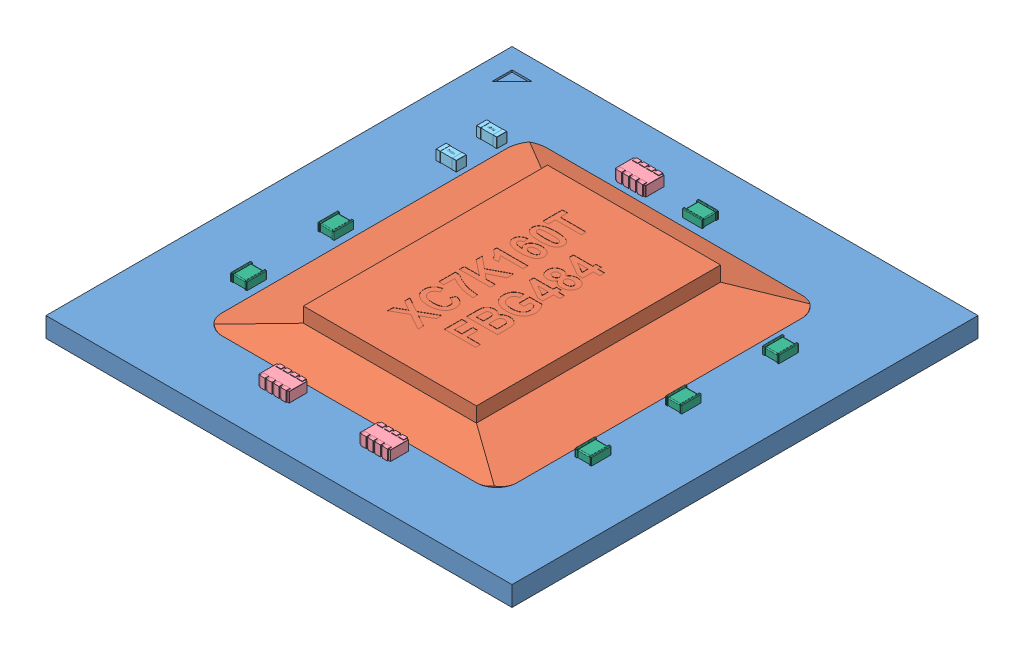
SolidWorks assembly FBG484, configuration Default. Lengths in mm.
Overall size (23 2.57 23).
25 component instances, 6 part files, 50 mates.
Components (placement in the parent):
- Substrate-1: Substrate [Default] at (0 0.3 0) size (23 0.98 23)
- Die-1: Die [Default] at (0 1.28 0) size (14.54 1.79 16.05)
- Ball-1: Ball [Default] at (10.5 0.15 -10.5) size (0.7 0.3 0.7)
- Ball-2: Ball [Default] at (10.5 0.15 -9.5) x (-1 0 0) z (0 0 1) size (0.7 0.3 0.7)
- Ball-3: Ball [Default] at (9.5 0.15 -10.5) x (0 0 -1) z (-1 0 0) size (0.7 0.3 0.7)
- Ball-4: Ball [Default] at (10.5 0.15 10.5) size (0.7 0.3 0.7)
- Ball-5: Ball [Default] at (10.5 0.15 9.5) x (-1 0 0) z (0 0 1) size (0.7 0.3 0.7)
- Ball-6: Ball [Default] at (9.5 0.15 10.5) x (0 0 1) z (1 0 0) size (0.7 0.3 0.7)
- Ball-7: Ball [Default] at (-10.5 0.15 -10.5) x (-1 0 0) z (0 0 -1) size (0.7 0.3 0.7)
- Ball-8: Ball [Default] at (-10.5 0.15 -9.5) x (1 0 0) z (0 0 -1) size (0.7 0.3 0.7)
- Ball-9: Ball [Default] at (-9.5 0.15 -10.5) x (0 0 -1) z (-1 0 0) size (0.7 0.3 0.7)
- Ball-10: Ball [Default] at (-10.5 0.15 10.5) x (-1 0 0) z (0 0 -1) size (0.7 0.3 0.7)
- Ball-11: Ball [Default] at (-10.5 0.15 9.5) x (1 0 0) z (0 0 -1) size (0.7 0.3 0.7)
- Ball-12: Ball [Default] at (-9.5 0.15 10.5) x (0 0 1) z (1 0 0) size (0.7 0.3 0.7)
- CARRAY-1: CARRAY [Default] at (-2.5 1.28 -8.8) size (1.5 0.52 1)
- CARRAY-2: CARRAY [Default] at (-2.5 1.28 8.8) size (1.5 0.52 1)
- CARRAY-3: CARRAY [Default] at (2.5 1.28 8.8) size (1.5 0.52 1)
- C0402-1: C0402 [0402] at (-8 1.28 -7) size (1 0.5 0.5)
- C0402-2: C0402 [0402] at (-8 1.28 -5) size (1 0.5 0.5)
- CWide-1: CWide [Default] at (-8 1.28 0.7) size (0.8 0.39 1)
- CWide-2: CWide [Default] at (-8 1.28 5) size (0.8 0.39 1)
- CWide-3: CWide [Default] at (8 1.28 4) size (0.8 0.39 1)
- CWide-4: CWide [Default] at (8 1.28 -0.45) size (0.8 0.39 1)
- CWide-5: CWide [Default] at (8.25 1.28 -5) size (0.8 0.39 1)
- CWide-6: CWide [Default] at (0.5 1.28 -8.8) x (0 0 -1) z (1 0 0) size (0.8 0.39 1)
Mates (geometry in assembly coordinates):
- Coincident1: coincident aligned: plane of Substrate-1 through (0 0.3 0) normal (1 0 0); plane of assembly through (0 0 0) normal (1 0 0)
- Coincident2: coincident aligned: plane of Substrate-1 through (0 0.3 0) normal (0 0 1); plane of assembly through (0 0 0) normal (0 0 1)
- Distance1: distance = 0.3 mm aligned: plane of Substrate-1 through (0 0.3 0) normal (0 1 0); plane of assembly through (0 0 0) normal (0 1 0)
- Coincident4: coincident aligned: plane of Die-1 through (0 1.28 0) normal (1 0 0); plane of assembly through (0 0 0) normal (1 0 0)
- Coincident5: coincident aligned: plane of Die-1 through (0 1.28 0) normal (0 0 1); plane of assembly through (0 0 0) normal (0 0 1)
- Distance2: distance = 0.5 mm anti-aligned: plane of Substrate-1 through (0 1.28 0) normal (0 1 0); plane of Die-1 through (0 0.78 0) normal (0 -1 0)
- Coincident7: coincident anti-aligned: plane of Substrate-1 through (0 0.3 0) normal (0 -1 0); plane of Ball-1 through (10.5 0.3 -10.5) normal (0 1 0)
- Distance4: distance = 10.5 mm aligned: plane of Ball-1 through (10.5 0.15 -10.5) normal (1 0 0); plane of assembly through (0 0 0) normal (1 0 0)
- Distance5: distance = 10.5 mm aligned: plane of Ball-1 through (10.5 0.15 -10.5) normal (0 0 1); plane of assembly through (0 0 0) normal (0 0 1)
- Coincident111: coincident anti-aligned: plane of Substrate-1 through (0 0.3 0) normal (0 -1 0); plane of Ball-2 through (10.5 0.3 -9.5) normal (0 1 0)
- Coincident121: coincident anti-aligned: plane of Substrate-1 through (0 0.3 0) normal (0 -1 0); plane of Ball-3 through (9.5 0.3 -10.5) normal (0 1 0)
- Coincident13: coincident anti-aligned: plane of Substrate-1 through (0 0.3 0) normal (0 -1 0); plane of Ball-2 through (10.5 0.3 -9.5) normal (0 1 0)
- Coincident14: coincident aligned: plane of Substrate-1 through (0 0.3 0) normal (0 -1 0); circle of Ball-3
- Distance6: distance = 1 mm aligned: plane of Ball-1 through (10.5 0.15 -10.5) normal (0 0 1); plane of Ball-2 through (10.5 0.15 -9.5) normal (0 0 1)
- Coincident16: coincident anti-aligned: plane of Ball-1 through (10.5 0.15 -10.5) normal (1 0 0); plane of Ball-2 through (10.5 0.15 -9.5) normal (-1 0 0)
- Distance7: distance = 1 mm anti-aligned: plane of Ball-1 through (10.5 0.15 -10.5) normal (1 0 0); plane of Ball-3 through (9.5 0.15 -10.5) normal (-1 0 0)
- Coincident18: coincident anti-aligned: plane of Ball-1 through (10.5 0.15 -10.5) normal (0 0 1); plane of Ball-3 through (9.5 0.15 -10.5) normal (0 0 -1)
- Coincident122: coincident anti-aligned: plane of Substrate-1 through (0 1.28 0) normal (0 1 0); plane of CARRAY-1 through (-2.5 1.28 -8.8) normal (0 -1 0)
- Distance8: distance = 2.5 mm aligned: plane of CARRAY-1 through (-2.5 1.28 -8.8) normal (1 0 0)
- Distance9: distance = 8.8 mm aligned: plane of CARRAY-1 through (-2.5 1.28 -8.8) normal (0 0 1)
- Distance10: distance = 8.8 mm: plane of assembly through (0 0 0) normal (0 0 1); plane of assembly; plane of CARRAY-2 through (-2.5 1.28 8.8) normal (0 0 1)
- Coincident126: coincident anti-aligned: plane of Substrate-1 through (0 1.28 0) normal (0 1 0); plane of CARRAY-2 through (-2.5 1.28 8.8) normal (0 -1 0)
- Coincident127: coincident anti-aligned: plane of Substrate-1 through (0 1.28 0) normal (0 1 0); plane of CARRAY-3 through (2.5 1.28 8.8) normal (0 -1 0)
- Distance11: distance = 2.5 mm: plane of assembly through (0 0 0) normal (1 0 0); plane of assembly; plane of CARRAY-2 through (-2.5 1.28 8.8) normal (1 0 0)
- Distance12: distance = 2.5 mm: plane of assembly through (0 0 0) normal (1 0 0); plane of assembly; plane of CARRAY-3 through (2.5 1.28 8.8) normal (1 0 0)
- Distance13: distance = 8.8 mm aligned: plane of CARRAY-3 through (2.5 1.28 8.8) normal (0 0 1)
- Distance14: distance = 8 mm aligned: plane of C0402-2 through (-8 1.28 -5) normal (1 0 0)
- Coincident132: coincident anti-aligned: plane of Substrate-1 through (0 1.28 0) normal (0 1 0); plane of C0402-2 through (-7.5 1.28 -4.75) normal (0 -1 0)
- Coincident133: coincident anti-aligned: plane of Substrate-1 through (0 1.28 0) normal (0 1 0); plane of C0402-1 through (-8.5 1.28 -6.75) normal (0 -1 0)
- Coincident134: coincident aligned: plane of C0402-1 through (-8 1.28 -7) normal (1 0 0); plane of C0402-2 through (-8 1.28 -5) normal (1 0 0)
- Distance15: distance = 7 mm aligned: plane of C0402-1 through (-8 1.28 -7) normal (0 0 1)
- Distance16: distance = 5 mm aligned: plane of C0402-2 through (-8 1.28 -5) normal (0 0 1)
- Distance17: distance = 8 mm aligned: plane of CWide-1 through (-8 1.28 0.7) normal (1 0 0)
- Distance18: distance = 0.7 mm aligned: plane of CWide-1 through (-8 1.28 0.7) normal (0 0 1)
- Coincident139: coincident anti-aligned: plane of Substrate-1 through (0 1.28 0) normal (0 1 0); plane of CWide-1 through (-8 1.28 0.7) normal (0 -1 0)
- Coincident140: coincident anti-aligned: plane of Substrate-1 through (0 1.28 0) normal (0 1 0); plane of CWide-2 through (-8 1.28 5) normal (0 -1 0)
- Coincident141: coincident aligned: plane of CWide-1 through (-8 1.28 0.7) normal (1 0 0); plane of CWide-2 through (-8 1.28 5) normal (1 0 0)
- Distance19: distance = 5 mm: plane of assembly through (0 0 0) normal (0 0 1); plane of assembly; plane of CWide-2 through (-8 1.28 5) normal (0 0 1)
- Coincident143: coincident anti-aligned: plane of Substrate-1 through (0 1.28 0) normal (0 1 0); plane of CWide-3 through (8 1.28 4) normal (0 -1 0)
- Coincident144: coincident anti-aligned: plane of Substrate-1 through (0 1.28 0) normal (0 1 0); plane of CWide-4 through (8 1.28 -0.45) normal (0 -1 0)
- Coincident145: coincident anti-aligned: plane of Substrate-1 through (0 1.28 0) normal (0 1 0); plane of CWide-5 through (8.25 1.28 -5) normal (0 -1 0)
- Distance20: distance = 8.25 mm aligned: plane of CWide-5 through (8.25 1.28 -5) normal (1 0 0)
- Distance21: distance = 8 mm aligned: plane of CWide-4 through (8 1.28 -0.45) normal (1 0 0)
- Coincident148: coincident aligned: plane of CWide-3 through (8 1.28 4) normal (1 0 0); plane of CWide-4 through (8 1.28 -0.45) normal (1 0 0)
- Distance22: distance = 0.45 mm aligned: plane of CWide-4 through (8 1.28 -0.45) normal (0 0 1)
- Distance23: distance = 5 mm: plane of assembly through (0 0 0) normal (0 0 1); plane of assembly; plane of CWide-5 through (8.25 1.28 -5) normal (0 0 1)
- Distance24: distance = 4 mm aligned: plane of CWide-3 through (8 1.28 4) normal (0 0 1)
- Coincident152: coincident anti-aligned: plane of Substrate-1 through (0 1.28 0) normal (0 1 0); plane of CWide-6 through (0.5 1.28 -8.8) normal (0 -1 0)
- Distance25: distance = 8.8 mm anti-aligned: plane of CWide-6 through (0.5 1.28 -8.8) normal (0 0 -1)
- Coincident154: coincident anti-aligned: plane of CWide-6 through (0 1.67 -9.1) normal (-1 0 0)
